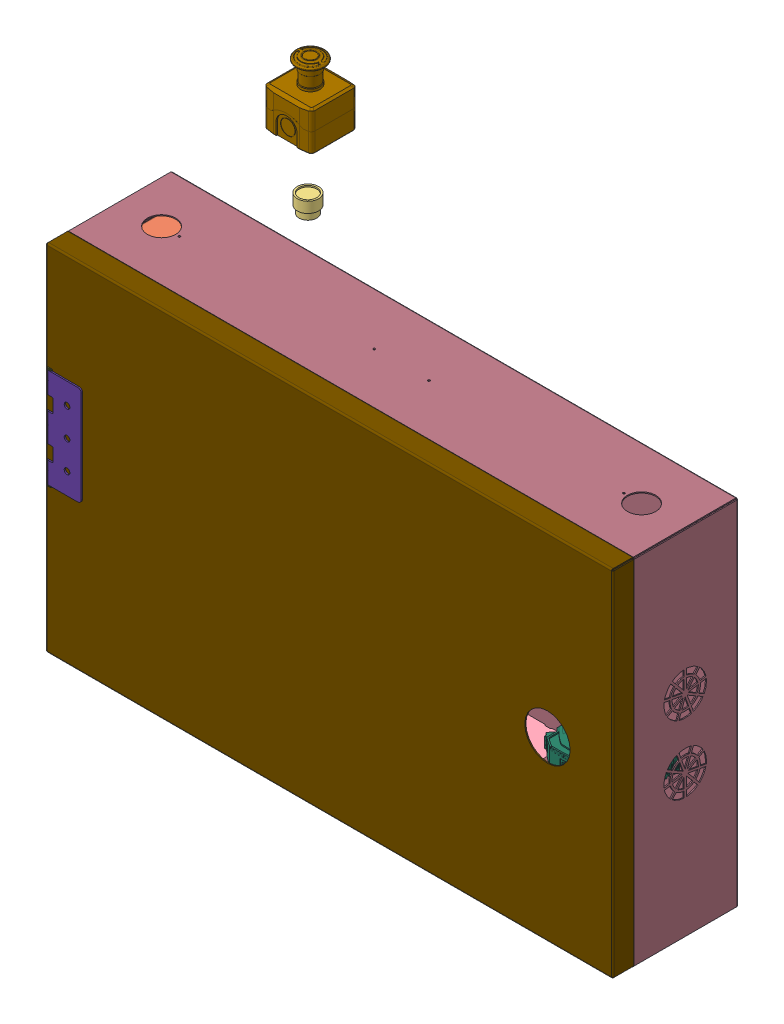
SolidWorks assembly EMERGENCY-simplified, configuration Default. Lengths in mm.
Overall size (807.91 1048.04 457.99).
31 component instances, 19 part files, 39 mates.
Components (placement in the parent):
- C16S2TM160_3D-SIMPLIFIED-1: C16S2TM160_3D-SIMPLIFIED [Default] at (1148.3871 -330.4144 407.009) x (1 0.000237 0) z (0 0 1) size (71.13 161.14 122.05)
- Nowforever_VFD-1: Nowforever_VFD [Default] at (985.0939 -31.9401 349.7855) size (87 142 124.5)
- Push Button-1: Push Button [Default] at (1577.326 617.9266 842.7537) size (30 25 30)
- q68davn_b-1: q68davn_b [Default] at (1347.6568 -288.4161 407.009) x (0 0 1) z (0 -1 0) size (112 109.5 27.4)
- SMPS-24v-1: SMPS-24v [Default] at (1069.2089 11.8644 364.5931) size (101.6 38.6 132.8)
  - Smps part 1-edit-00-1: Smps part 1-edit-00 [Default] at (3.0479 73.0195 107.4159) size (101.6 38.6 132.8)
  - Smps part 2-edit-00-1: Smps part 2-edit-00 [Default] at (3.0479 73.0195 109.9159) size (100 37 119)
  - part3-edit-00-1: part3-edit-00 [Default] at (3.0479 36.0195 107.4159) x (1 0 0) z (0 1 0) size (92.52 118.51 25)
  - pan cross head_am_B18.6.7M - M5 x 0.8 x 10 Type I Cross Recessed PHMS --10N-1: pan cross head_am_B18.6.7M - M5 x 0.8 x 10 Type I Cross Recessed PHMS --10N [Default] at (83.1766 48.7195 51.7585) x (0 -1 0) z (0 0 1) size (13.86 9.5 9.57)
  - pan cross head_am_B18.6.7M - M5 x 0.8 x 10 Type I Cross Recessed PHMS --10N-2: pan cross head_am_B18.6.7M - M5 x 0.8 x 10 Type I Cross Recessed PHMS --10N [Default] at (74.1766 48.7195 51.7585) x (0 -1 0) z (0 0 1) size (13.86 9.5 9.57)
  - pan cross head_am_B18.6.7M - M5 x 0.8 x 10 Type I Cross Recessed PHMS --10N-3: pan cross head_am_B18.6.7M - M5 x 0.8 x 10 Type I Cross Recessed PHMS --10N [Default] at (65.1766 48.7195 51.7585) x (0 -1 0) z (0 0 1) size (13.86 9.5 9.57)
  - pan cross head_am_B18.6.7M - M5 x 0.8 x 10 Type I Cross Recessed PHMS --10N-4: pan cross head_am_B18.6.7M - M5 x 0.8 x 10 Type I Cross Recessed PHMS --10N [Default] at (56.1766 48.7195 51.7585) x (0 -1 0) z (0 0 1) size (13.86 9.5 9.57)
  - pan cross head_am_B18.6.7M - M5 x 0.8 x 10 Type I Cross Recessed PHMS --10N-5: pan cross head_am_B18.6.7M - M5 x 0.8 x 10 Type I Cross Recessed PHMS --10N [Default] at (47.1766 48.7195 51.7585) x (0 -1 0) z (0 0 1) size (13.86 9.5 9.57)
- User Library-Estop-1: User Library-Estop [Default] at (1452.5119 594.9214 714.5488) size (67 89.5 67)
- FX5UJ-40MT-1: FX5UJ-40MT [默认] at (1465.6568 -85.1161 404.009) size (130 97.4 85)
- LP1K0910BD_3D-1: LP1K0910BD_3D [Default] at (1428.2266 9.7513 455.7729) size (45 56.7 58)
  - PRODUCT_ID_76-1: PRODUCT_ID_76 [Default] at (-57.0692 0.2126 -27.0136) size (45 56.7 58)
  - PRODUCT_ID_77-1: PRODUCT_ID_77 [Default] at (-57.0692 0.2126 -28.4636) size (45 1.78 46.4)
- Part1^EMERGENCY-simplified-1: Part1^EMERGENCY-simplified [Default] at origin (virtual)
- main body-1: main body [Default] at (1347.1568 -113.6161 407.009) size (800.01 500 168.5)
- DOP-B03S211-1: DOP-B03S211 [Default] at (1236.5618 -46.1658 445.229) size (128.63 102.63 40.22)
- C16S2TM160_3D-SIMPLIFIED-2: C16S2TM160_3D-SIMPLIFIED [Default] at (1048.6568 -337.3861 407.009) size (71.13 161.14 122.05)
- q68davn_b-2: q68davn_b [Default] at (1467.6568 -288.8161 407.009) x (0 0 1) z (0 -1 0) size (112 109.5 27.4)
- 1085039-1: 1085039 [Default] at (1542.6531 -215.1161 400.5503) x (0 -1 0) z (0 0 1) size (22.73 123.01 90.09)
- Hinge Assembly-2: Hinge Assembly [Default] at (955.59 -83.3394 582.7724) x (0.997288 0 0.073599) z (0 1 0) size (50.45 11.66 144.5)
  - part 3-1: part 3 [Default] at origin size (8 8 144.5)
  - Part 1-1: Part 1 [Default] at (46.0224 1.391 70) x (0 0 -1) z (-0.073599 0.997288 0) size (140 50 8)
- Hinge Assembly-3: Hinge Assembly [Default] at (949.1568 -85.2442 563.7274) x (-0.073599 0 -0.997288) z (0 -1 0) size (50.45 11.66 144.5)
  - part 3-1: part 3 [Default] at origin size (8 8 144.5)
  - Part 1-1: Part 1 [Default] at (46.0224 1.391 70) x (0 0 -1) z (-0.073599 0.997288 0) size (140 50 8)
- gate-2: gate [Default] at (1349.3934 -111.1161 584.7724) size (800 500 31.5)
Mates (geometry in assembly coordinates):
- Coincident1: coincident anti-aligned: plane of Nowforever_VFD-1 through (1050.1568 -11.6161 407.009) normal (0 0 -1); plane of main body-1 through (1347.1568 -113.6161 407.009) normal (0 0 1)
- Distance1: distance = 20 mm anti-aligned: plane of main body-1 through (948.6568 -113.6161 407.009) normal (1 0 0); plane of Nowforever_VFD-1 through (968.6568 124.8839 522.009) normal (-1 0 0)
- Distance2: distance = 10 mm anti-aligned: plane of Nowforever_VFD-1 through (968.6568 124.8839 522.009) normal (0 1 0); plane of main body-1 through (1347.1568 134.8839 407.009) normal (0 -1 0)
- Coincident5: coincident anti-aligned: plane of SMPS-24v-1/Smps part 1-edit-00-1 through (1073.4568 49.0839 407.009) normal (0 0 -1); plane of main body-1 through (1347.1568 -113.6161 407.009) normal (0 0 1)
- Parallel1: parallel anti-aligned: plane of Nowforever_VFD-1 through (1055.6568 124.8839 522.009) normal (1 0 0); plane of SMPS-24v-1/Smps part 1-edit-00-1 through (1070.6568 84.8839 537.009) normal (-1 0 0)
- Distance3: distance = 50 mm anti-aligned: plane of SMPS-24v-1/Smps part 2-edit-00-1 through (1072.2568 84.8839 532.009) normal (0 1 0); plane of main body-1 through (1347.1568 134.8839 407.009) normal (0 -1 0)
- Distance4: distance = 15 mm anti-aligned: plane of SMPS-24v-1/Smps part 1-edit-00-1 through (1070.6568 84.8839 537.009) normal (-1 0 0); plane of Nowforever_VFD-1 through (1055.6568 124.8839 522.009) normal (1 0 0)
- Coincident12: coincident anti-aligned: plane of main body-1 through (1347.1568 -113.6161 407.009) normal (0 0 1); plane of DOP-B03S211-1 through (1236.5618 -46.1658 407.009) normal (0 0 -1)
- Distance10: distance = 230 mm anti-aligned: plane of DOP-B03S211-1 through (1178.6568 -21.1658 413.439) normal (-1 0 0); plane of main body-1 through (948.6568 -113.6161 407.009) normal (1 0 0)
- Distance11: distance = 330 mm anti-aligned: plane of C16S2TM160_3D-SIMPLIFIED-2 through (1118.3568 -195.1161 407.009) normal (0 1 0); plane of main body-1 through (1347.1568 134.8839 407.009) normal (0 -1 0)
- Coincident14: coincident anti-aligned: plane of main body-1 through (1347.1568 -113.6161 407.009) normal (0 0 1); plane of C16S2TM160_3D-SIMPLIFIED-2 through (1048.6568 -337.3861 407.009) normal (0 0 -1)
- Distance13: distance = 100 mm anti-aligned: plane of C16S2TM160_3D-SIMPLIFIED-2 through (1048.6568 -196.8718 407.009) normal (-1 0 0); plane of main body-1 through (948.6568 -113.6161 407.009) normal (1 0 0)
- Distance14: distance = 30 mm anti-aligned: plane of C16S2TM160_3D-SIMPLIFIED-1 through (1148.3537 -189.9001 407.009) normal (-1 -0.000237 0); plane of C16S2TM160_3D-SIMPLIFIED-2 through (1118.3838 -316.6219 407.009) normal (1 0.000237 0)
- Coincident18: coincident anti-aligned: plane of C16S2TM160_3D-SIMPLIFIED-1 through (1148.3871 -330.4144 407.009) normal (0 0 -1); plane of main body-1 through (1347.1568 -113.6161 407.009) normal (0 0 1)
- Distance16: distance = 50 mm anti-aligned: plane of C16S2TM160_3D-SIMPLIFIED-1 through (1153.2765 -312.1161 487.809) normal (0 -1 0); plane of main body-1 through (1347.1568 -362.1161 407.009) normal (0 1 0)
- Distance17: distance = 60 mm anti-aligned: plane of q68davn_b-1 through (1396.6568 -302.1161 485.809) normal (0 -1 0); plane of main body-1 through (1347.1568 -362.1161 407.009) normal (0 1 0)
- Coincident22: coincident anti-aligned: plane of q68davn_b-1 through (1298.6568 -302.1161 407.009) normal (0 0 -1); plane of main body-1 through (1347.1568 -113.6161 407.009) normal (0 0 1)
- Distance21: distance = 130 mm: plane of main body-1 through (1347.1568 134.8839 407.009) normal (0 -1 0); line of DOP-B03S211-1 through (1174.2446 4.8839 444.2813) axis (1 0 0)
- Distance24: distance = 350 mm anti-aligned: plane of main body-1 through (948.6568 -113.6161 407.009) normal (1 0 0); plane of q68davn_b-1 through (1298.6568 -302.1161 485.809) normal (-1 0 0)
- Coincident31: coincident anti-aligned: plane of main body-1 through (1347.1568 -113.6161 407.009) normal (0 0 1); plane of q68davn_b-2 through (1418.6568 -302.5161 407.009) normal (0 0 -1)
- Distance25: distance = 470 mm anti-aligned: plane of q68davn_b-2 through (1418.6568 -302.5161 485.809) normal (-1 0 0); plane of main body-1 through (948.6568 -113.6161 407.009) normal (1 0 0)
- Distance26: distance = 410 mm anti-aligned: plane of q68davn_b-2 through (1516.6568 -275.1161 485.809) normal (0 1 0); plane of main body-1 through (1347.1568 134.8839 407.009) normal (0 -1 0)
- Coincident34: coincident anti-aligned: plane of LP1K0910BD_3D-1/PRODUCT_ID_76-1 through (1371.1574 -12.2008 407.009) normal (0 0 -1); plane of main body-1 through (1347.1568 -113.6161 407.009) normal (0 0 1)
- Coincident35: coincident anti-aligned: plane of FX5UJ-40MT-1 through (1465.6568 -85.1161 407.009) normal (0 0 -1); plane of main body-1 through (1347.1568 -113.6161 407.009) normal (0 0 1)
- Distance27: distance = 400 mm anti-aligned: plane of LP1K0910BD_3D-1/PRODUCT_ID_76-1 through (1348.6568 -46.7365 399.7589) normal (-1 0 0); plane of main body-1 through (948.6568 -113.6161 407.009) normal (1 0 0)
- Distance28: distance = 130 mm anti-aligned: plane of LP1K0910BD_3D-1/PRODUCT_ID_76-1 through (1371.1574 4.8839 428.7593) normal (0 1 0); plane of main body-1 through (1347.1568 134.8839 407.009) normal (0 -1 0)
- Distance29: distance = 150 mm anti-aligned: plane of FX5UJ-40MT-1 through (1595.6568 -40.1161 404.009) normal (1 0 0); plane of main body-1 through (1745.6568 -113.6161 407.009) normal (-1 0 0)
- Distance30: distance = 130 mm anti-aligned: plane of FX5UJ-40MT-1 through (1465.6568 4.8839 407.009) normal (0 1 0); plane of main body-1 through (1347.1568 134.8839 407.009) normal (0 -1 0)
- Coincident43: coincident anti-aligned: plane of main body-1 through (1347.1568 -113.6161 407.009) normal (0 0 1); plane of 1085039-1 through (1648.3876 -226.3626 407.009) normal (0 0 -1)
- Distance34: distance = 80 mm anti-aligned: plane of 1085039-1 through (1665.6568 -215.1161 405.58) normal (1 0 0); plane of main body-1 through (1745.6568 -113.6161 407.009) normal (-1 0 0)
- Distance36: distance = 350 mm anti-aligned: plane of 1085039-1 through (1618.0747 -215.1161 410.3531) normal (0 1 0); plane of main body-1 through (1347.1568 134.8839 407.009) normal (0 -1 0)
- Coincident54: coincident anti-aligned: plane of main body-1 through (947.1568 -113.6161 407.009) normal (-1 0 0); plane of Hinge Assembly-3/Part 1-1 through (947.1568 -155.2442 517.7274) normal (1 0 0)
- Distance39: distance = 110 mm: line of main body-1 through (947.1568 -361.9747 407.7456) axis (0 1 0); line of Hinge Assembly-3/Part 1-1 through (945.1568 -150.2442 517.7274) axis (0 1 0)
- Coincident57: coincident anti-aligned: line of main body-1 through (949.3934 -361.2381 555.509) axis (0 1 0); line of gate-2 through (949.3934 137.2425 555.509) axis (0 -1 0)
- Distance40: distance = 1 mm anti-aligned: plane of main body-1 through (1347.1568 -362.1161 407.009) normal (0 1 0); plane of gate-2 through (1349.3934 -361.1161 584.7724) normal (0 -1 0)
- Coincident59: coincident anti-aligned: plane of Hinge Assembly-2/Part 1-1 through (1001.59 -13.3394 584.7724) normal (0 0 -1); plane of gate-2 through (1349.3934 -111.1161 584.7724) normal (0 0 1)
- Distance41: distance = 50 mm: line of Hinge Assembly-2/Part 1-1 through (1001.59 -18.3394 586.7724) axis (0 -1 0); line of gate-2 through (951.63 136.6473 584.7724) axis (0 -1 0)
- Distance42: distance = 150 mm: line of Hinge Assembly-2/Part 1-1 through (955.59 -13.3394 586.7724) axis (1 0 0); line of gate-2 through (1747.1568 136.6473 584.7724) axis (-1 0 0)
- Distance44: distance = 150 mm: line of Hinge Assembly-3/Part 1-1 through (945.1568 -15.2442 522.7274) axis (0 0 1); line of main body-1 through (947.1568 134.7425 407.7456) axis (0 0 1)
